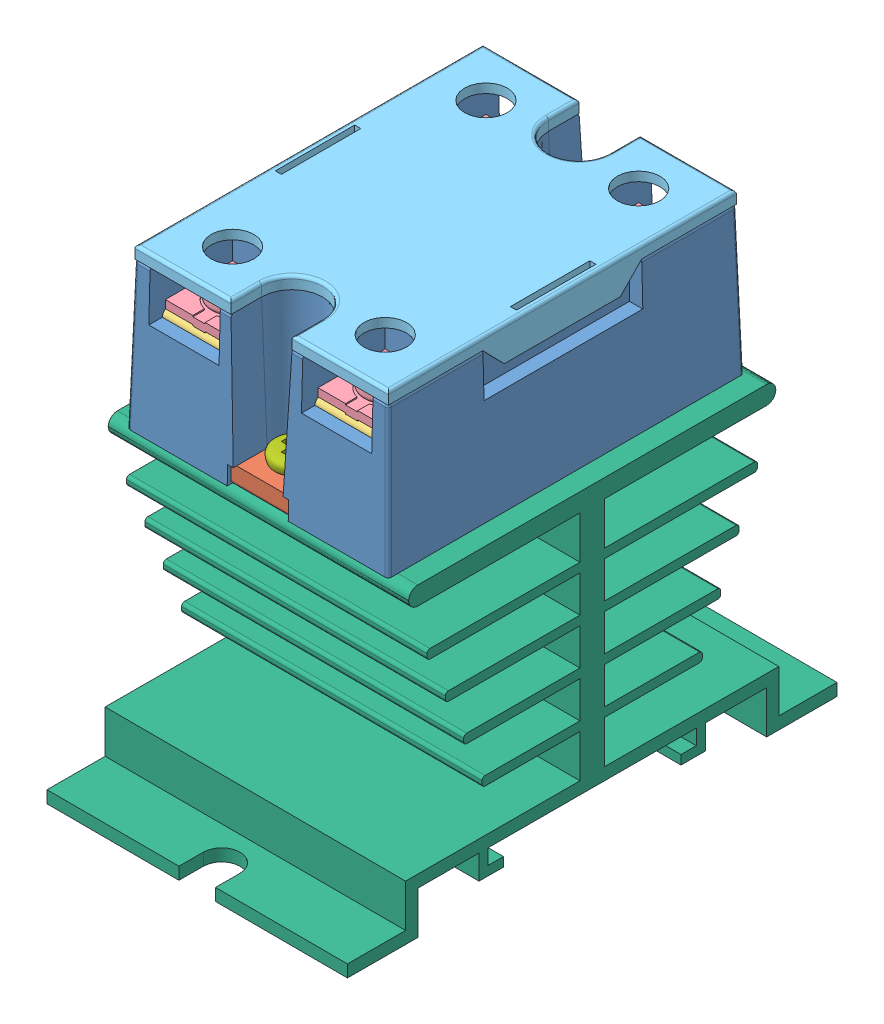
SolidWorks assembly SE1206.Uxcell.SSR-25.A02.Final.Assembly.with.Heat.Sink, configuration Default. Lengths in mm.
Overall size (49.47 76 80.1).
15 component instances, 7 part files, 11 mates.
Components (placement in the parent):
- SE1206.Uxcell.SSR-25.A01.Final.Assembly-1: SE1206.Uxcell.SSR-25.A01.Final.Assembly [Default] at (0 50 0) size (42.76 26 58.26)
  - SE1206.Uxcell.SSR-25.B01.SSR.Body-1: SE1206.Uxcell.SSR-25.B01.SSR.Body [Default] at origin size (42.76 24 58.26)
  - SE1206.Uxcell.SSR-25.B02.Metal.Back.Cover-1: SE1206.Uxcell.SSR-25.B02.Metal.Back.Cover [Default] at origin size (38.5 3 57)
  - SE1206.Uxcell.SSR-25.B03.Metal.Contact-1: SE1206.Uxcell.SSR-25.B03.Metal.Contact [Default] at (-12.5 15 20.75) size (11.5 2 11.5)
  - SE1206.Uxcell.SSR-25.B03.Metal.Contact-2: SE1206.Uxcell.SSR-25.B03.Metal.Contact [Default] at (12.5 15 20.75) size (11.5 2 11.5)
  - SE1206.Uxcell.SSR-25.B03.Metal.Contact-3: SE1206.Uxcell.SSR-25.B03.Metal.Contact [Default] at (-12.5 15 -20.75) x (-1 0 0) z (0 0 -1) size (11.5 2 11.5)
  - SE1206.Uxcell.SSR-25.B03.Metal.Contact-4: SE1206.Uxcell.SSR-25.B03.Metal.Contact [Default] at (12.5 15 -20.75) x (-1 0 0) z (0 0 -1) size (11.5 2 11.5)
  - SE1206.Uxcell.SSR-25.B04.Contact.Bolt-1: SE1206.Uxcell.SSR-25.B04.Contact.Bolt [Default] at (-12.5 18.5 20.75) size (11 12.09 11)
  - SE1206.Uxcell.SSR-25.B04.Contact.Bolt-2: SE1206.Uxcell.SSR-25.B04.Contact.Bolt [Default] at (12.5 18.5 20.75) x (-1 0 0) z (0 0 -1) size (11 12.09 11)
  - SE1206.Uxcell.SSR-25.B04.Contact.Bolt-3: SE1206.Uxcell.SSR-25.B04.Contact.Bolt [Default] at (-12.5 18.5 -20.75) size (11 12.09 11)
  - SE1206.Uxcell.SSR-25.B04.Contact.Bolt-4: SE1206.Uxcell.SSR-25.B04.Contact.Bolt [Default] at (12.5 18.5 -20.75) x (-1 0 0) z (0 0 -1) size (11 12.09 11)
  - SE1206.Uxcell.SSR-25.B05.Clear.Front.Cover-3: SE1206.Uxcell.SSR-25.B05.Clear.Front.Cover [Default] at (0 24 0) size (41.5 5.6 57)
- SE1206.Uxcell.SSR-25.B06.Heat.Sink-1: SE1206.Uxcell.SSR-25.B06.Heat.Sink [Default] at (0.05 7 -0.9999) x (0.999998 0 0.002083) z (-0.002083 0 0.999998) size (49.3 50 80)
- SE1206.Uxcell.SSR-25.B07.Heat.Sink.Bolt-1: SE1206.Uxcell.SSR-25.B07.Heat.Sink.Bolt [Default] at (0 53 23) x (0.999998 0 0.002083) z (-0.002083 0 0.999998) size (7.26 10.07 7.26)
- SE1206.Uxcell.SSR-25.B07.Heat.Sink.Bolt-3: SE1206.Uxcell.SSR-25.B07.Heat.Sink.Bolt [Default] at (0.1 53 -24.9999) x (0.999998 0 0.002083) z (-0.002083 0 0.999998) size (7.26 10.07 7.26)
Mates (geometry in assembly coordinates):
- Coincident1: coincident anti-aligned: plane of ? through (0 50 0) normal (0 -1 0); plane of SE1206.Uxcell.SSR-25.B06.Heat.Sink-1 through (24.6999 50 -0.9486) normal (0 1 0)
- Concentric1: concentric aligned: cylinder of ? through (0 50 23) axis (0 1 0) radius 2.5; cylinder of SE1206.Uxcell.SSR-25.B06.Heat.Sink-1 through (0 41.3431 23) axis (0 1 0) radius 2
- Coincident2: coincident aligned: plane of ? through (0 50 0) normal (0 0 1); plane of assembly through (0 0 0) normal (0 0 1)
- Coincident3: coincident aligned: plane of ? through (0 50 0) normal (1 0 0); plane of assembly through (0 0 0) normal (1 0 0)
- Coincident4: coincident anti-aligned: plane of SE1206.Uxcell.SSR-25.B06.Heat.Sink-1 through (24.7593 0 -29.4485) normal (0 -1 0); plane of assembly through (0 0 0) normal (0 1 0)
- Concentric2: concentric aligned: cylinder of SE1206.Uxcell.SSR-25.B06.Heat.Sink-1 through (0 41.3431 23) axis (0 1 0) radius 2; cylinder of SE1206.Uxcell.SSR-25.B07.Heat.Sink.Bolt-1 through (0 45 23) axis (0 1 0) radius 2
- Coincident5: coincident anti-aligned: plane of ? through (0 53 0) normal (0 1 0); plane of SE1206.Uxcell.SSR-25.B07.Heat.Sink.Bolt-1 through (0 53 23) normal (0 -1 0)
- Concentric3: concentric aligned: cylinder of SE1206.Uxcell.SSR-25.B06.Heat.Sink-1 through (0.1 41.3431 -24.9999) axis (0 1 0) radius 2; cylinder of SE1206.Uxcell.SSR-25.B07.Heat.Sink.Bolt-3 through (0.1 45 -24.9999) axis (0 1 0) radius 2
- Coincident6: coincident anti-aligned: plane of ? through (0 53 0) normal (0 1 0); plane of SE1206.Uxcell.SSR-25.B07.Heat.Sink.Bolt-3 through (0.1 53 -24.9999) normal (0 -1 0)
- Coincident7: coincident aligned: line of SE1206.Uxcell.SSR-25.B07.Heat.Sink.Bolt-1 through (-1.7892 54.1 22.7065) axis (-0.002083 0 0.999998); line of SE1206.Uxcell.SSR-25.B07.Heat.Sink.Bolt-3 through (-1.6892 54.1 -25.2934) axis (-0.002083 0 0.999998)
- Tangent1: tangent anti-aligned: plane of ? through (2.1 50 -28.5) normal (-1 0 0); cylinder of SE1206.Uxcell.SSR-25.B07.Heat.Sink.Bolt-3 through (0.1 45 -24.9999) axis (0 1 0) radius 2
